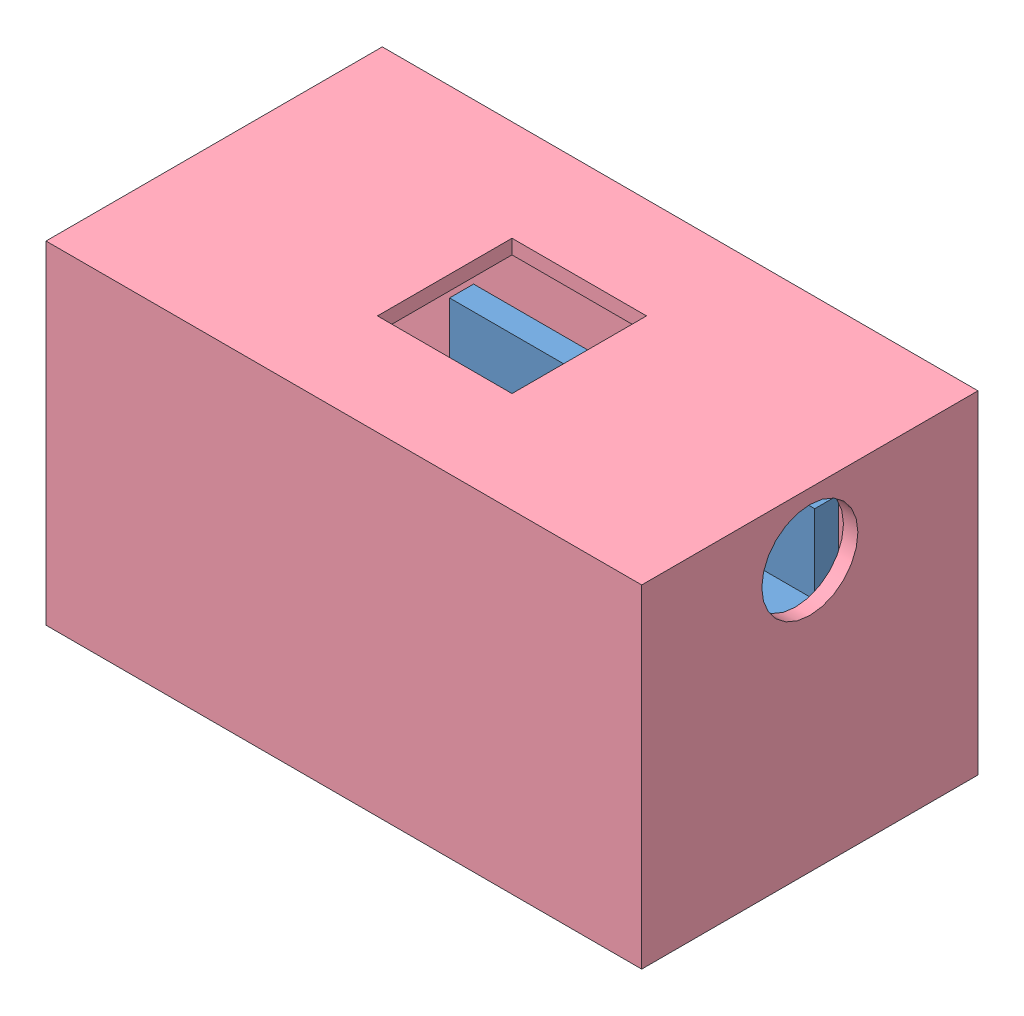
SolidWorks assembly 装配体3, configuration 默认. Lengths in mm.
Overall size (62 34.63 35).
7 component instances, 4 part files, 12 mates.
Components (placement in the parent):
- esp8266New-2: esp8266New [默认] at (-13.2603 -2.2228 59.048) x (1 0 0) z (0 0 -1) size (57 12.9 30.4)
- CopperPillar-1: CopperPillar [默认] at (-30.1605 -8.8228 44.7) x (1 0 0) z (0 1 0) size (5.31 4.63 8)
- CopperPillar-2: CopperPillar [默认] at (21.8395 -8.8228 44.7) x (1 0 0) z (0 1 0) size (5.31 4.63 8)
- CopperPillar-3: CopperPillar [默认] at (21.8395 -8.8228 69.3) x (1 0 0) z (0 1 0) size (5.31 4.63 8)
- CopperPillar-4: CopperPillar [默认] at (-30.1605 -8.8228 69.3) x (1 0 0) z (0 1 0) size (5.31 4.63 8)
- DiKe2-1: DiKe2 [默认] at (-8.0224 -14.3228 52.4657) size (59 5.5 32)
- ShangKe-1: ShangKe [默认] at (-7.1573 16.3064 61.7518) size (62 34.63 35)
Mates (geometry in assembly coordinates):
- 重合1: coincident anti-aligned: circle of esp8266New-2; plane of CopperPillar-1 through (-30.1605 -3.8228 44.7) normal (0 1 0)
- 重合2: coincident anti-aligned: plane of esp8266New-2 through (-13.2603 -3.8228 59.048) normal (0 -1 0); plane of CopperPillar-4 through (-30.1605 -3.8228 69.3) normal (0 1 0)
- 重合3: coincident anti-aligned: plane of esp8266New-2 through (-13.2603 -3.8228 59.048) normal (0 -1 0); plane of CopperPillar-2 through (21.8395 -3.8228 44.7) normal (0 1 0)
- 重合4: coincident anti-aligned: plane of esp8266New-2 through (-13.2603 -3.8228 59.048) normal (0 -1 0); plane of CopperPillar-3 through (21.8395 -3.8228 69.3) normal (0 1 0)
- 同心1: concentric aligned: circle of esp8266New-2; circle of CopperPillar-1
- 同心2: concentric aligned: circle of esp8266New-2; circle of CopperPillar-4
- 同心3: concentric aligned: circle of esp8266New-2; circle of CopperPillar-3
- 同心4: concentric aligned: circle of esp8266New-2; circle of CopperPillar-2
- 重合13: coincident anti-aligned: plane of CopperPillar-3 through (21.8395 -8.8228 69.3) normal (0 -1 0); plane of DiKe2-1 through (21.8395 -8.8228 69.3) normal (0 1 0)
- 距离1: distance = 1.5 mm aligned: plane of ShangKe-1 through (-35.1605 17.8064 74.5) normal (0 0 1); plane of DiKe2-1 through (-32.6605 -14.3228 73) normal (0 0 1)
- 距离2: distance = 1.5 mm aligned: plane of DiKe2-1 through (-33.6605 -46.3384 41) normal (-1 0 0); plane of ShangKe-1 through (-35.1605 17.8064 39.5) normal (-1 0 0)
- 同心5: concentric anti-aligned: cylinder of esp8266New-2 through (-30.1605 -2.2228 69.3) axis (0 -1 0) radius 1.5; circle of DiKe2-1
